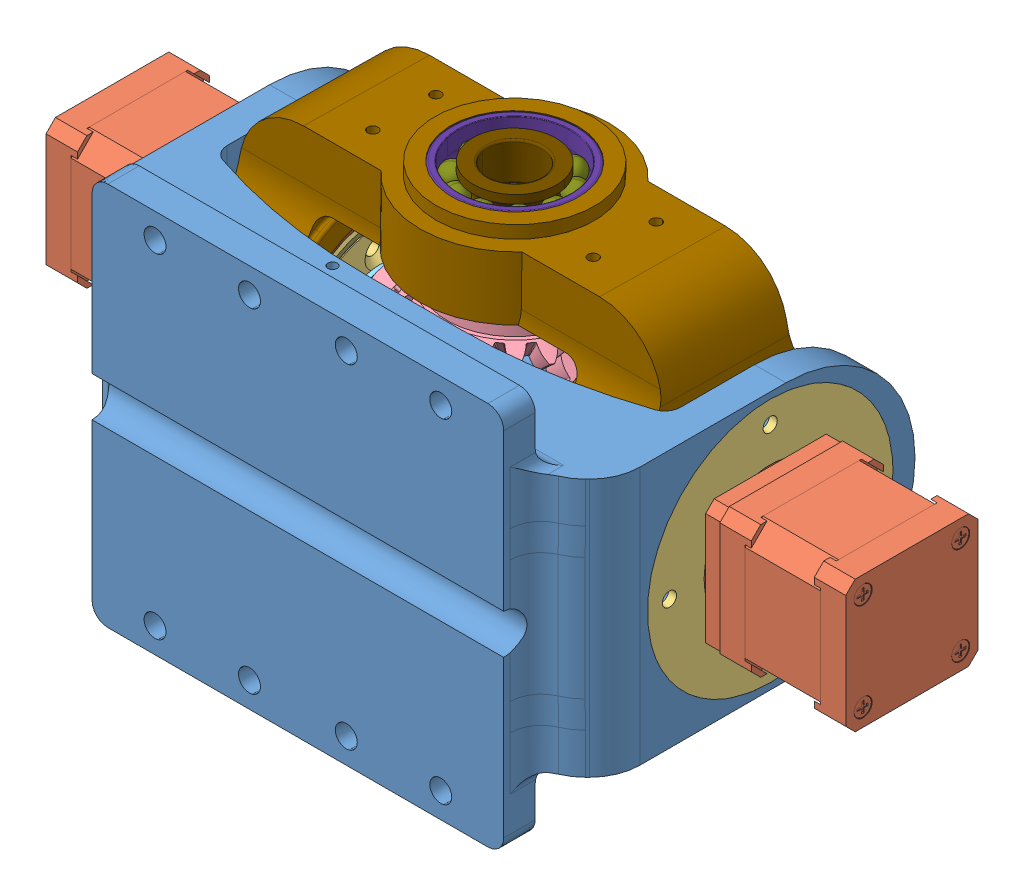
SolidWorks assembly UOM20-4A004, configuration Default. Lengths in mm.
Overall size (254 124.53 114).
231 component instances, 22 part files, 40 mates.
Components (placement in the parent):
- Wrist input frame-1: Wrist input frame [Default] at (121.1695 -112.5132 10.5195) x (0 0 1) z (-1 0 0) size (114 122 164)
- 17HS15-1684D-HG10-AR3-1: 17HS15-1684D-HG10-AR3 [Default] at (87 0 -68) x (0 0 -1) z (-1 0 0) size (42.88 42 103.5)
- Motor sleeve-1: Motor sleeve [Default] at (82 0 -68) x (-1 0 0) z (0 0 1) size (40 78 78)
- straight miter gear_am-1: straight miter gear_am [A 1C 4MYKW25020] at (27.6259 0 -68) x (-1 0 0) z (0 -0.979897 0.199505) size (19.66 53.34 53.34)
- 1.5mm spacer-3: 1.5mm spacer [Default] at (37 0 -68) x (0 0 -1) z (1 0 0) size (28 28 1.5)
- AXK_1528___AS_1528___AS_1528-2: AXK_1528___AS_1528___AS_1528 [Default] at (39.5 0 -68) size (4 28 28)
  - AXK_1528___AS_1528___AS_1528_3-1: AXK_1528___AS_1528___AS_1528_3 [Default] x (1 0 0) z (0 -0.309017 0.951057) size (2 5 2)
  - AXK_1528___AS_1528___AS_1528_3-2: AXK_1528___AS_1528___AS_1528_3 [Default] x (1 0 0) z (0 -0.587785 0.809017) size (2 5 2)
  - AXK_1528___AS_1528___AS_1528_3-3: AXK_1528___AS_1528___AS_1528_3 [Default] x (1 0 0) z (0 -0.809017 0.587785) size (2 5 2)
  - AXK_1528___AS_1528___AS_1528_3-4: AXK_1528___AS_1528___AS_1528_3 [Default] x (1 0 0) z (0 -0.951057 0.309017) size (2 5 2)
  - AXK_1528___AS_1528___AS_1528_3-5: AXK_1528___AS_1528___AS_1528_3 [Default] x (1 0 0) z (0 -1 0) size (2 5 2)
  - AXK_1528___AS_1528___AS_1528_3-6: AXK_1528___AS_1528___AS_1528_3 [Default] x (1 0 0) z (0 -0.951057 -0.309017) size (2 5 2)
  - AXK_1528___AS_1528___AS_1528_3-7: AXK_1528___AS_1528___AS_1528_3 [Default] x (1 0 0) z (0 -0.809017 -0.587785) size (2 5 2)
  - AXK_1528___AS_1528___AS_1528_3-8: AXK_1528___AS_1528___AS_1528_3 [Default] x (1 0 0) z (0 -0.587785 -0.809017) size (2 5 2)
  - AXK_1528___AS_1528___AS_1528_3-9: AXK_1528___AS_1528___AS_1528_3 [Default] x (1 0 0) z (0 -0.309017 -0.951057) size (2 5 2)
  - AXK_1528___AS_1528___AS_1528_3-10: AXK_1528___AS_1528___AS_1528_3 [Default] x (1 0 0) z (0 0 -1) size (2 5 2)
  - AXK_1528___AS_1528___AS_1528_3-11: AXK_1528___AS_1528___AS_1528_3 [Default] x (1 0 0) z (0 0.309017 -0.951057) size (2 5 2)
  - AXK_1528___AS_1528___AS_1528_3-12: AXK_1528___AS_1528___AS_1528_3 [Default] x (1 0 0) z (0 0.587785 -0.809017) size (2 5 2)
  - AXK_1528___AS_1528___AS_1528_3-13: AXK_1528___AS_1528___AS_1528_3 [Default] x (1 0 0) z (0 0.809017 -0.587785) size (2 5 2)
  - AXK_1528___AS_1528___AS_1528_3-14: AXK_1528___AS_1528___AS_1528_3 [Default] x (1 0 0) z (0 0.951057 -0.309017) size (2 5 2)
  - AXK_1528___AS_1528___AS_1528_3-15: AXK_1528___AS_1528___AS_1528_3 [Default] x (1 0 0) z (0 1 0) size (2 5 2)
  - AXK_1528___AS_1528___AS_1528_3-16: AXK_1528___AS_1528___AS_1528_3 [Default] x (1 0 0) z (0 0.951057 0.309017) size (2 5 2)
  - AXK_1528___AS_1528___AS_1528_3-17: AXK_1528___AS_1528___AS_1528_3 [Default] x (1 0 0) z (0 0.809017 0.587785) size (2 5 2)
  - AXK_1528___AS_1528___AS_1528_3-18: AXK_1528___AS_1528___AS_1528_3 [Default] x (1 0 0) z (0 0.587785 0.809017) size (2 5 2)
  - AXK_1528___AS_1528___AS_1528_3-19: AXK_1528___AS_1528___AS_1528_3 [Default] x (1 0 0) z (0 0.309017 0.951057) size (2 5 2)
  - AXK_1528___AS_1528___AS_1528_3-20: AXK_1528___AS_1528___AS_1528_3 [Default] at origin size (2 5 2)
  - AXK_1528___AS_1528___AS_1528_24-1: AXK_1528___AS_1528___AS_1528_24 [Default] at origin size (1 28 28) (hidden)
  - AXK_1528___AS_1528___AS_1528_26-1: AXK_1528___AS_1528___AS_1528_26 [Default] at origin size (1 28 28) (hidden)
  - AXK_1528___AS_1528___AS_1528_28-1: AXK_1528___AS_1528___AS_1528_28 [Default] at origin size (1.6 28 28)
- 1.5mm spacer-4: 1.5mm spacer [Default] at (42 0 -68) x (0 0.929021 0.370027) z (-1 0 0) size (28 28 1.5)
- Input shaft-1: Input shaft [Default] at (42 0 -68) x (-1 0 0) z (0 0.979897 -0.199505) size (42 17 17)
- Wrist output frame-1: Wrist output frame [Default] at (-67 0 -68) x (1 0 0) z (0 0.013642 0.999907) size (134 102 78)
- NKI_50_25-1: NKI_50_25 [Default] at (-67 0 -68) size (25 68.42 68)
  - NKI_50_25_37-1: NKI_50_25_37 [Default] x (1 0 0) z (0 -0.189251 0.981929) size (18.8 3.5 3.5)
  - NKI_50_25_37-2: NKI_50_25_37 [Default] x (1 0 0) z (0 -0.371662 0.928368) size (18.8 3.5 3.5)
  - NKI_50_25_37-3: NKI_50_25_37 [Default] x (1 0 0) z (0 -0.540641 0.841254) size (18.8 3.5 3.5)
  - NKI_50_25_37-4: NKI_50_25_37 [Default] x (1 0 0) z (0 -0.690079 0.723734) size (18.8 3.5 3.5)
  - NKI_50_25_37-5: NKI_50_25_37 [Default] x (1 0 0) z (0 -0.814576 0.580057) size (18.8 3.5 3.5)
  - NKI_50_25_37-6: NKI_50_25_37 [Default] x (1 0 0) z (0 -0.909632 0.415415) size (18.8 3.5 3.5)
  - NKI_50_25_37-7: NKI_50_25_37 [Default] x (1 0 0) z (0 -0.971812 0.235759) size (18.8 3.5 3.5)
  - NKI_50_25_37-8: NKI_50_25_37 [Default] x (1 0 0) z (0 -0.998867 0.047582) size (18.8 3.5 3.5)
  - NKI_50_25_37-9: NKI_50_25_37 [Default] x (1 0 0) z (0 -0.989821 -0.142315) size (18.8 3.5 3.5)
  - NKI_50_25_37-10: NKI_50_25_37 [Default] x (1 0 0) z (0 -0.945001 -0.327068) size (18.8 3.5 3.5)
  - NKI_50_25_37-11: NKI_50_25_37 [Default] x (1 0 0) z (0 -0.866025 -0.5) size (18.8 3.5 3.5)
  - NKI_50_25_37-12: NKI_50_25_37 [Default] x (1 0 0) z (0 -0.75575 -0.654861) size (18.8 3.5 3.5)
  - NKI_50_25_37-13: NKI_50_25_37 [Default] x (1 0 0) z (0 -0.618159 -0.786053) size (18.8 3.5 3.5)
  - NKI_50_25_37-14: NKI_50_25_37 [Default] x (1 0 0) z (0 -0.458227 -0.888835) size (18.8 3.5 3.5)
  - NKI_50_25_37-15: NKI_50_25_37 [Default] x (1 0 0) z (0 -0.281733 -0.959493) size (18.8 3.5 3.5)
  - NKI_50_25_37-16: NKI_50_25_37 [Default] x (1 0 0) z (0 -0.095056 -0.995472) size (18.8 3.5 3.5)
  - NKI_50_25_37-17: NKI_50_25_37 [Default] x (1 0 0) z (0 0.095056 -0.995472) size (18.8 3.5 3.5)
  - NKI_50_25_37-18: NKI_50_25_37 [Default] x (1 0 0) z (0 0.281733 -0.959493) size (18.8 3.5 3.5)
  - NKI_50_25_37-19: NKI_50_25_37 [Default] x (1 0 0) z (0 0.458227 -0.888835) size (18.8 3.5 3.5)
  - NKI_50_25_37-20: NKI_50_25_37 [Default] x (1 0 0) z (0 0.618159 -0.786053) size (18.8 3.5 3.5)
  - NKI_50_25_37-21: NKI_50_25_37 [Default] x (1 0 0) z (0 0.75575 -0.654861) size (18.8 3.5 3.5)
  - NKI_50_25_37-22: NKI_50_25_37 [Default] x (1 0 0) z (0 0.866025 -0.5) size (18.8 3.5 3.5)
  - NKI_50_25_37-23: NKI_50_25_37 [Default] x (1 0 0) z (0 0.945001 -0.327068) size (18.8 3.5 3.5)
  - NKI_50_25_37-24: NKI_50_25_37 [Default] x (1 0 0) z (0 0.989821 -0.142315) size (18.8 3.5 3.5)
  - NKI_50_25_37-25: NKI_50_25_37 [Default] x (1 0 0) z (0 0.998867 0.047582) size (18.8 3.5 3.5)
  - NKI_50_25_37-26: NKI_50_25_37 [Default] x (1 0 0) z (0 0.971812 0.235759) size (18.8 3.5 3.5)
  - NKI_50_25_37-27: NKI_50_25_37 [Default] x (1 0 0) z (0 0.909632 0.415415) size (18.8 3.5 3.5)
  - NKI_50_25_37-28: NKI_50_25_37 [Default] x (1 0 0) z (0 0.814576 0.580057) size (18.8 3.5 3.5)
  - NKI_50_25_37-29: NKI_50_25_37 [Default] x (1 0 0) z (0 0.690079 0.723734) size (18.8 3.5 3.5)
  - NKI_50_25_37-30: NKI_50_25_37 [Default] x (1 0 0) z (0 0.540641 0.841254) size (18.8 3.5 3.5)
  - NKI_50_25_37-31: NKI_50_25_37 [Default] x (1 0 0) z (0 0.371662 0.928368) size (18.8 3.5 3.5)
  - NKI_50_25_37-32: NKI_50_25_37 [Default] x (1 0 0) z (0 0.189251 0.981929) size (18.8 3.5 3.5)
  - NKI_50_25_37-33: NKI_50_25_37 [Default] at origin size (18.8 3.5 3.5)
  - NKI_50_25_71-1: NKI_50_25_71 [Default] at origin size (25 68.42 68)
  - NKI_50_25_73-1: NKI_50_25_73 [Default] at origin size (25 55 55)
- HK_1412-1: HK_1412 [Default] at (-15 0 -68) x (1 0 0) z (0 0.280515 0.95985) size (12 20 20)
  - HK_1412_3-1: HK_1412_3 [Default] x (1 0 0) z (0 -0.382683 0.92388) size (7.3 2 2)
  - HK_1412_3-2: HK_1412_3 [Default] x (1 0 0) z (0 -0.707107 0.707107) size (7.3 2 2)
  - HK_1412_3-3: HK_1412_3 [Default] x (1 0 0) z (0 -0.92388 0.382683) size (7.3 2 2)
  - HK_1412_3-4: HK_1412_3 [Default] x (1 0 0) z (0 -1 0) size (7.3 2 2)
  - HK_1412_3-5: HK_1412_3 [Default] x (1 0 0) z (0 -0.92388 -0.382683) size (7.3 2 2)
  - HK_1412_3-6: HK_1412_3 [Default] x (1 0 0) z (0 -0.707107 -0.707107) size (7.3 2 2)
  - HK_1412_3-7: HK_1412_3 [Default] x (1 0 0) z (0 -0.382683 -0.92388) size (7.3 2 2)
  - HK_1412_3-8: HK_1412_3 [Default] x (1 0 0) z (0 0 -1) size (7.3 2 2)
  - HK_1412_3-9: HK_1412_3 [Default] x (1 0 0) z (0 0.382683 -0.92388) size (7.3 2 2)
  - HK_1412_3-10: HK_1412_3 [Default] x (1 0 0) z (0 0.707107 -0.707107) size (7.3 2 2)
  - HK_1412_3-11: HK_1412_3 [Default] x (1 0 0) z (0 0.92388 -0.382683) size (7.3 2 2)
  - HK_1412_3-12: HK_1412_3 [Default] x (1 0 0) z (0 1 0) size (7.3 2 2)
  - HK_1412_3-13: HK_1412_3 [Default] x (1 0 0) z (0 0.92388 0.382683) size (7.3 2 2)
  - HK_1412_3-14: HK_1412_3 [Default] x (1 0 0) z (0 0.707107 0.707107) size (7.3 2 2)
  - HK_1412_3-15: HK_1412_3 [Default] x (1 0 0) z (0 0.382683 0.92388) size (7.3 2 2)
  - HK_1412_3-16: HK_1412_3 [Default] at origin size (7.3 2 2)
  - HK_1412_20-1: HK_1412_20 [Default] x (1 0 0) z (0 -0.382683 0.92388) size (7.3 2 2)
  - HK_1412_20-2: HK_1412_20 [Default] x (1 0 0) z (0 -0.707107 0.707107) size (7.3 2 2)
  - HK_1412_20-3: HK_1412_20 [Default] x (1 0 0) z (0 -0.92388 0.382683) size (7.3 2 2)
  - HK_1412_20-4: HK_1412_20 [Default] x (1 0 0) z (0 -1 0) size (7.3 2 2)
  - HK_1412_20-5: HK_1412_20 [Default] x (1 0 0) z (0 -0.92388 -0.382683) size (7.3 2 2)
  - HK_1412_20-6: HK_1412_20 [Default] x (1 0 0) z (0 -0.707107 -0.707107) size (7.3 2 2)
  - HK_1412_20-7: HK_1412_20 [Default] x (1 0 0) z (0 -0.382683 -0.92388) size (7.3 2 2)
  - HK_1412_20-8: HK_1412_20 [Default] x (1 0 0) z (0 0 -1) size (7.3 2 2)
  - HK_1412_20-9: HK_1412_20 [Default] x (1 0 0) z (0 0.382683 -0.92388) size (7.3 2 2)
  - HK_1412_20-10: HK_1412_20 [Default] x (1 0 0) z (0 0.707107 -0.707107) size (7.3 2 2)
  - HK_1412_20-11: HK_1412_20 [Default] x (1 0 0) z (0 0.92388 -0.382683) size (7.3 2 2)
  - HK_1412_20-12: HK_1412_20 [Default] x (1 0 0) z (0 1 0) size (7.3 2 2)
  - HK_1412_20-13: HK_1412_20 [Default] x (1 0 0) z (0 0.92388 0.382683) size (7.3 2 2)
  - HK_1412_20-14: HK_1412_20 [Default] x (1 0 0) z (0 0.707107 0.707107) size (7.3 2 2)
  - HK_1412_20-15: HK_1412_20 [Default] x (1 0 0) z (0 0.382683 0.92388) size (7.3 2 2)
  - HK_1412_20-16: HK_1412_20 [Default] at origin size (7.3 2 2)
  - HK_1412_37-1: HK_1412_37 [Default] at origin size (12 20 20)
- Output shaft-1: Output shaft [Default] at (0 18.9482 -68.2585) x (-0.666543 0.01017 0.745397) z (0 0.999907 -0.013642) size (110 110 15) (hidden)
- 7203_BEY-1: 7203_BEY [Default] at (0 38.9964 -68.532) x (0 0.999907 -0.013642) z (0.969629 -0.003337 -0.244559) size (12 40 40)
  - 7203_BEY_3-1: 7203_BEY_3 [Default] x (1 0 0) z (0 -0.587785 0.809017) size (7.14 7.14 7.14)
  - 7203_BEY_3-2: 7203_BEY_3 [Default] x (1 0 0) z (0 -0.951057 0.309017) size (7.14 7.14 7.14)
  - 7203_BEY_3-3: 7203_BEY_3 [Default] x (1 0 0) z (0 -0.951057 -0.309017) size (7.14 7.14 7.14)
  - 7203_BEY_3-4: 7203_BEY_3 [Default] x (1 0 0) z (0 -0.587785 -0.809017) size (7.14 7.14 7.14)
  - 7203_BEY_3-5: 7203_BEY_3 [Default] x (1 0 0) z (0 0 -1) size (7.14 7.14 7.14)
  - 7203_BEY_3-6: 7203_BEY_3 [Default] x (1 0 0) z (0 0.587785 -0.809017) size (7.14 7.14 7.14)
  - 7203_BEY_3-7: 7203_BEY_3 [Default] x (1 0 0) z (0 0.951057 -0.309017) size (7.14 7.14 7.14)
  - 7203_BEY_3-8: 7203_BEY_3 [Default] x (1 0 0) z (0 0.951057 0.309017) size (7.14 7.14 7.14)
  - 7203_BEY_3-9: 7203_BEY_3 [Default] x (1 0 0) z (0 0.587785 0.809017) size (7.14 7.14 7.14)
  - 7203_BEY_3-10: 7203_BEY_3 [Default] at origin size (7.14 7.14 7.14)
  - 7203_BEY_14-1: 7203_BEY_14 [Default] at origin size (12 40 40)
  - 7203_BEY_16-1: 7203_BEY_16 [Default] at origin size (12 26.25 26.25)
- 7203_BEY-2: 7203_BEY [Default] at (0 50.9953 -68.6957) x (0 0.999907 -0.013642) z (0.973748 -0.003105 -0.227608) size (12 40 40)
  - 7203_BEY_3-1: 7203_BEY_3 [Default] x (1 0 0) z (0 -0.587785 0.809017) size (7.14 7.14 7.14)
  - 7203_BEY_3-2: 7203_BEY_3 [Default] x (1 0 0) z (0 -0.951057 0.309017) size (7.14 7.14 7.14)
  - 7203_BEY_3-3: 7203_BEY_3 [Default] x (1 0 0) z (0 -0.951057 -0.309017) size (7.14 7.14 7.14)
  - 7203_BEY_3-4: 7203_BEY_3 [Default] x (1 0 0) z (0 -0.587785 -0.809017) size (7.14 7.14 7.14)
  - 7203_BEY_3-5: 7203_BEY_3 [Default] x (1 0 0) z (0 0 -1) size (7.14 7.14 7.14)
  - 7203_BEY_3-6: 7203_BEY_3 [Default] x (1 0 0) z (0 0.587785 -0.809017) size (7.14 7.14 7.14)
  - 7203_BEY_3-7: 7203_BEY_3 [Default] x (1 0 0) z (0 0.951057 -0.309017) size (7.14 7.14 7.14)
  - 7203_BEY_3-8: 7203_BEY_3 [Default] x (1 0 0) z (0 0.951057 0.309017) size (7.14 7.14 7.14)
  - 7203_BEY_3-9: 7203_BEY_3 [Default] x (1 0 0) z (0 0.587785 0.809017) size (7.14 7.14 7.14)
  - 7203_BEY_3-10: 7203_BEY_3 [Default] at origin size (7.14 7.14 7.14)
  - 7203_BEY_14-1: 7203_BEY_14 [Default] at origin size (12 40 40)
  - 7203_BEY_16-1: 7203_BEY_16 [Default] at origin size (12 26.25 26.25)
- straight miter gear_am-3: straight miter gear_am [A 1C 4MYKW25020] at (0 29.6232 -68.4042) x (0 -0.999907 0.013642) z (0.288342 -0.013063 -0.957438) size (19.66 53.34 53.34)
- Wrist output cap-1: Wrist output cap [Default] at (0 62.9941 -68.8594) x (-1 0 0) z (0 0.999907 -0.013642) size (94 60 6.33) (hidden)
- straight miter gear_am-2: straight miter gear_am [A 1C 4MYKW25020] at (-27.6259 0 -68) x (1 0 0) z (0 0.979897 -0.199505) size (19.66 53.34 53.34)
- 1.5mm spacer-5: 1.5mm spacer [Default] at (-38.5 0 -68) x (0 0 -1) z (1 0 0) size (28 28 1.5)
- AXK_1528___AS_1528___AS_1528-3: AXK_1528___AS_1528___AS_1528 [Default] at (-39.5 0 -68) x (-1 0 0) z (0 0 -1) size (4 28 28)
  - AXK_1528___AS_1528___AS_1528_3-1: AXK_1528___AS_1528___AS_1528_3 [Default] x (1 0 0) z (0 -0.309017 0.951057) size (2 5 2)
  - AXK_1528___AS_1528___AS_1528_3-2: AXK_1528___AS_1528___AS_1528_3 [Default] x (1 0 0) z (0 -0.587785 0.809017) size (2 5 2)
  - AXK_1528___AS_1528___AS_1528_3-3: AXK_1528___AS_1528___AS_1528_3 [Default] x (1 0 0) z (0 -0.809017 0.587785) size (2 5 2)
  - AXK_1528___AS_1528___AS_1528_3-4: AXK_1528___AS_1528___AS_1528_3 [Default] x (1 0 0) z (0 -0.951057 0.309017) size (2 5 2)
  - AXK_1528___AS_1528___AS_1528_3-5: AXK_1528___AS_1528___AS_1528_3 [Default] x (1 0 0) z (0 -1 0) size (2 5 2)
  - AXK_1528___AS_1528___AS_1528_3-6: AXK_1528___AS_1528___AS_1528_3 [Default] x (1 0 0) z (0 -0.951057 -0.309017) size (2 5 2)
  - AXK_1528___AS_1528___AS_1528_3-7: AXK_1528___AS_1528___AS_1528_3 [Default] x (1 0 0) z (0 -0.809017 -0.587785) size (2 5 2)
  - AXK_1528___AS_1528___AS_1528_3-8: AXK_1528___AS_1528___AS_1528_3 [Default] x (1 0 0) z (0 -0.587785 -0.809017) size (2 5 2)
  - AXK_1528___AS_1528___AS_1528_3-9: AXK_1528___AS_1528___AS_1528_3 [Default] x (1 0 0) z (0 -0.309017 -0.951057) size (2 5 2)
  - AXK_1528___AS_1528___AS_1528_3-10: AXK_1528___AS_1528___AS_1528_3 [Default] x (1 0 0) z (0 0 -1) size (2 5 2)
  - AXK_1528___AS_1528___AS_1528_3-11: AXK_1528___AS_1528___AS_1528_3 [Default] x (1 0 0) z (0 0.309017 -0.951057) size (2 5 2)
  - AXK_1528___AS_1528___AS_1528_3-12: AXK_1528___AS_1528___AS_1528_3 [Default] x (1 0 0) z (0 0.587785 -0.809017) size (2 5 2)
  - AXK_1528___AS_1528___AS_1528_3-13: AXK_1528___AS_1528___AS_1528_3 [Default] x (1 0 0) z (0 0.809017 -0.587785) size (2 5 2)
  - AXK_1528___AS_1528___AS_1528_3-14: AXK_1528___AS_1528___AS_1528_3 [Default] x (1 0 0) z (0 0.951057 -0.309017) size (2 5 2)
  - AXK_1528___AS_1528___AS_1528_3-15: AXK_1528___AS_1528___AS_1528_3 [Default] x (1 0 0) z (0 1 0) size (2 5 2)
  - AXK_1528___AS_1528___AS_1528_3-16: AXK_1528___AS_1528___AS_1528_3 [Default] x (1 0 0) z (0 0.951057 0.309017) size (2 5 2)
  - AXK_1528___AS_1528___AS_1528_3-17: AXK_1528___AS_1528___AS_1528_3 [Default] x (1 0 0) z (0 0.809017 0.587785) size (2 5 2)
  - AXK_1528___AS_1528___AS_1528_3-18: AXK_1528___AS_1528___AS_1528_3 [Default] x (1 0 0) z (0 0.587785 0.809017) size (2 5 2)
  - AXK_1528___AS_1528___AS_1528_3-19: AXK_1528___AS_1528___AS_1528_3 [Default] x (1 0 0) z (0 0.309017 0.951057) size (2 5 2)
  - AXK_1528___AS_1528___AS_1528_3-20: AXK_1528___AS_1528___AS_1528_3 [Default] at origin size (2 5 2)
  - AXK_1528___AS_1528___AS_1528_24-1: AXK_1528___AS_1528___AS_1528_24 [Default] at origin size (1 28 28) (hidden)
  - AXK_1528___AS_1528___AS_1528_26-1: AXK_1528___AS_1528___AS_1528_26 [Default] at origin size (1 28 28) (hidden)
  - AXK_1528___AS_1528___AS_1528_28-1: AXK_1528___AS_1528___AS_1528_28 [Default] at origin size (1.6 28 28)
- 1.5mm spacer-6: 1.5mm spacer [Default] at (-40.5 0 -68) x (0 0.929021 0.370027) z (-1 0 0) size (28 28 1.5)
- Input shaft-2: Input shaft [Default] at (-42 0 -68) x (1 0 0) z (0 -0.979897 0.199505) size (42 17 17)
- HK_1412-2: HK_1412 [Default] at (15 0 -68) x (-1 0 0) z (0 -0.280515 -0.95985) size (12 20 20)
  - HK_1412_3-1: HK_1412_3 [Default] x (1 0 0) z (0 -0.382683 0.92388) size (7.3 2 2)
  - HK_1412_3-2: HK_1412_3 [Default] x (1 0 0) z (0 -0.707107 0.707107) size (7.3 2 2)
  - HK_1412_3-3: HK_1412_3 [Default] x (1 0 0) z (0 -0.92388 0.382683) size (7.3 2 2)
  - HK_1412_3-4: HK_1412_3 [Default] x (1 0 0) z (0 -1 0) size (7.3 2 2)
  - HK_1412_3-5: HK_1412_3 [Default] x (1 0 0) z (0 -0.92388 -0.382683) size (7.3 2 2)
  - HK_1412_3-6: HK_1412_3 [Default] x (1 0 0) z (0 -0.707107 -0.707107) size (7.3 2 2)
  - HK_1412_3-7: HK_1412_3 [Default] x (1 0 0) z (0 -0.382683 -0.92388) size (7.3 2 2)
  - HK_1412_3-8: HK_1412_3 [Default] x (1 0 0) z (0 0 -1) size (7.3 2 2)
  - HK_1412_3-9: HK_1412_3 [Default] x (1 0 0) z (0 0.382683 -0.92388) size (7.3 2 2)
  - HK_1412_3-10: HK_1412_3 [Default] x (1 0 0) z (0 0.707107 -0.707107) size (7.3 2 2)
  - HK_1412_3-11: HK_1412_3 [Default] x (1 0 0) z (0 0.92388 -0.382683) size (7.3 2 2)
  - HK_1412_3-12: HK_1412_3 [Default] x (1 0 0) z (0 1 0) size (7.3 2 2)
  - HK_1412_3-13: HK_1412_3 [Default] x (1 0 0) z (0 0.92388 0.382683) size (7.3 2 2)
  - HK_1412_3-14: HK_1412_3 [Default] x (1 0 0) z (0 0.707107 0.707107) size (7.3 2 2)
  - HK_1412_3-15: HK_1412_3 [Default] x (1 0 0) z (0 0.382683 0.92388) size (7.3 2 2)
  - HK_1412_3-16: HK_1412_3 [Default] at origin size (7.3 2 2)
  - HK_1412_20-1: HK_1412_20 [Default] x (1 0 0) z (0 -0.382683 0.92388) size (7.3 2 2)
  - HK_1412_20-2: HK_1412_20 [Default] x (1 0 0) z (0 -0.707107 0.707107) size (7.3 2 2)
  - HK_1412_20-3: HK_1412_20 [Default] x (1 0 0) z (0 -0.92388 0.382683) size (7.3 2 2)
  - HK_1412_20-4: HK_1412_20 [Default] x (1 0 0) z (0 -1 0) size (7.3 2 2)
  - HK_1412_20-5: HK_1412_20 [Default] x (1 0 0) z (0 -0.92388 -0.382683) size (7.3 2 2)
  - HK_1412_20-6: HK_1412_20 [Default] x (1 0 0) z (0 -0.707107 -0.707107) size (7.3 2 2)
  - HK_1412_20-7: HK_1412_20 [Default] x (1 0 0) z (0 -0.382683 -0.92388) size (7.3 2 2)
  - HK_1412_20-8: HK_1412_20 [Default] x (1 0 0) z (0 0 -1) size (7.3 2 2)
  - HK_1412_20-9: HK_1412_20 [Default] x (1 0 0) z (0 0.382683 -0.92388) size (7.3 2 2)
  - HK_1412_20-10: HK_1412_20 [Default] x (1 0 0) z (0 0.707107 -0.707107) size (7.3 2 2)
  - HK_1412_20-11: HK_1412_20 [Default] x (1 0 0) z (0 0.92388 -0.382683) size (7.3 2 2)
  - HK_1412_20-12: HK_1412_20 [Default] x (1 0 0) z (0 1 0) size (7.3 2 2)
  - HK_1412_20-13: HK_1412_20 [Default] x (1 0 0) z (0 0.92388 0.382683) size (7.3 2 2)
  - HK_1412_20-14: HK_1412_20 [Default] x (1 0 0) z (0 0.707107 0.707107) size (7.3 2 2)
  - HK_1412_20-15: HK_1412_20 [Default] x (1 0 0) z (0 0.382683 0.92388) size (7.3 2 2)
  - HK_1412_20-16: HK_1412_20 [Default] at origin size (7.3 2 2)
  - HK_1412_37-1: HK_1412_37 [Default] at origin size (12 20 20)
- 17HS15-1684D-HG10-AR3-2: 17HS15-1684D-HG10-AR3 [Default] at (-87 0 -68) x (0 0 -1) z (1 0 0) size (42.88 42 103.5)
- Motor sleeve-2: Motor sleeve [Default] at (-82 0 -68) size (40 78 78)
- NKI_50_25-2: NKI_50_25 [Default] at (42 0 -68) size (25 68.42 68)
  - NKI_50_25_37-1: NKI_50_25_37 [Default] x (1 0 0) z (0 -0.189251 0.981929) size (18.8 3.5 3.5)
  - NKI_50_25_37-2: NKI_50_25_37 [Default] x (1 0 0) z (0 -0.371662 0.928368) size (18.8 3.5 3.5)
  - NKI_50_25_37-3: NKI_50_25_37 [Default] x (1 0 0) z (0 -0.540641 0.841254) size (18.8 3.5 3.5)
  - NKI_50_25_37-4: NKI_50_25_37 [Default] x (1 0 0) z (0 -0.690079 0.723734) size (18.8 3.5 3.5)
  - NKI_50_25_37-5: NKI_50_25_37 [Default] x (1 0 0) z (0 -0.814576 0.580057) size (18.8 3.5 3.5)
  - NKI_50_25_37-6: NKI_50_25_37 [Default] x (1 0 0) z (0 -0.909632 0.415415) size (18.8 3.5 3.5)
  - NKI_50_25_37-7: NKI_50_25_37 [Default] x (1 0 0) z (0 -0.971812 0.235759) size (18.8 3.5 3.5)
  - NKI_50_25_37-8: NKI_50_25_37 [Default] x (1 0 0) z (0 -0.998867 0.047582) size (18.8 3.5 3.5)
  - NKI_50_25_37-9: NKI_50_25_37 [Default] x (1 0 0) z (0 -0.989821 -0.142315) size (18.8 3.5 3.5)
  - NKI_50_25_37-10: NKI_50_25_37 [Default] x (1 0 0) z (0 -0.945001 -0.327068) size (18.8 3.5 3.5)
  - NKI_50_25_37-11: NKI_50_25_37 [Default] x (1 0 0) z (0 -0.866025 -0.5) size (18.8 3.5 3.5)
  - NKI_50_25_37-12: NKI_50_25_37 [Default] x (1 0 0) z (0 -0.75575 -0.654861) size (18.8 3.5 3.5)
  - NKI_50_25_37-13: NKI_50_25_37 [Default] x (1 0 0) z (0 -0.618159 -0.786053) size (18.8 3.5 3.5)
  - NKI_50_25_37-14: NKI_50_25_37 [Default] x (1 0 0) z (0 -0.458227 -0.888835) size (18.8 3.5 3.5)
  - NKI_50_25_37-15: NKI_50_25_37 [Default] x (1 0 0) z (0 -0.281733 -0.959493) size (18.8 3.5 3.5)
  - NKI_50_25_37-16: NKI_50_25_37 [Default] x (1 0 0) z (0 -0.095056 -0.995472) size (18.8 3.5 3.5)
  - NKI_50_25_37-17: NKI_50_25_37 [Default] x (1 0 0) z (0 0.095056 -0.995472) size (18.8 3.5 3.5)
  - NKI_50_25_37-18: NKI_50_25_37 [Default] x (1 0 0) z (0 0.281733 -0.959493) size (18.8 3.5 3.5)
  - NKI_50_25_37-19: NKI_50_25_37 [Default] x (1 0 0) z (0 0.458227 -0.888835) size (18.8 3.5 3.5)
  - NKI_50_25_37-20: NKI_50_25_37 [Default] x (1 0 0) z (0 0.618159 -0.786053) size (18.8 3.5 3.5)
  - NKI_50_25_37-21: NKI_50_25_37 [Default] x (1 0 0) z (0 0.75575 -0.654861) size (18.8 3.5 3.5)
  - NKI_50_25_37-22: NKI_50_25_37 [Default] x (1 0 0) z (0 0.866025 -0.5) size (18.8 3.5 3.5)
  - NKI_50_25_37-23: NKI_50_25_37 [Default] x (1 0 0) z (0 0.945001 -0.327068) size (18.8 3.5 3.5)
  - NKI_50_25_37-24: NKI_50_25_37 [Default] x (1 0 0) z (0 0.989821 -0.142315) size (18.8 3.5 3.5)
  - NKI_50_25_37-25: NKI_50_25_37 [Default] x (1 0 0) z (0 0.998867 0.047582) size (18.8 3.5 3.5)
  - NKI_50_25_37-26: NKI_50_25_37 [Default] x (1 0 0) z (0 0.971812 0.235759) size (18.8 3.5 3.5)
  - NKI_50_25_37-27: NKI_50_25_37 [Default] x (1 0 0) z (0 0.909632 0.415415) size (18.8 3.5 3.5)
  - NKI_50_25_37-28: NKI_50_25_37 [Default] x (1 0 0) z (0 0.814576 0.580057) size (18.8 3.5 3.5)
  - NKI_50_25_37-29: NKI_50_25_37 [Default] x (1 0 0) z (0 0.690079 0.723734) size (18.8 3.5 3.5)
  - NKI_50_25_37-30: NKI_50_25_37 [Default] x (1 0 0) z (0 0.540641 0.841254) size (18.8 3.5 3.5)
  - NKI_50_25_37-31: NKI_50_25_37 [Default] x (1 0 0) z (0 0.371662 0.928368) size (18.8 3.5 3.5)
  - NKI_50_25_37-32: NKI_50_25_37 [Default] x (1 0 0) z (0 0.189251 0.981929) size (18.8 3.5 3.5)
  - NKI_50_25_37-33: NKI_50_25_37 [Default] at origin size (18.8 3.5 3.5)
  - NKI_50_25_71-1: NKI_50_25_71 [Default] at origin size (25 68.42 68)
  - NKI_50_25_73-1: NKI_50_25_73 [Default] at origin size (25 55 55)
Mates (geometry in assembly coordinates):
- Coincident2: coincident aligned: plane of Wrist input frame-1 through (121.1695 -112.5132 0) normal (0 0 1)
- Symmetric2: symmetric aligned: plane of Wrist input frame-1 through (0 41 -10) normal (0 1 0); plane of Wrist input frame-1 through (0 -41 -10) normal (0 -1 0)
- Symmetric1: symmetric aligned: plane of Wrist input frame-1 through (82 -41 -10) normal (1 0 0); plane of Wrist input frame-1 through (-82 -41 -10) normal (-1 0 0)
- Concentric1: concentric aligned: cylinder of 17HS15-1684D-HG10-AR3-1 through (47 0 -68) axis (1 0 0) radius 21; cylinder of Motor sleeve-1 through (146.1034 0 -68) axis (1 0 0) radius 21
- Concentric2: concentric aligned: cylinder of 17HS15-1684D-HG10-AR3-1 through (47 0 -50.5) axis (-1 0 0) radius 2.25; cylinder of Motor sleeve-1 through (42 0 -50.5) axis (-1 0 0) radius 2.25
- Concentric3: concentric aligned: cylinder of 17HS15-1684D-HG10-AR3-1 through (47 17.5 -68) axis (-1 0 0) radius 2.25; cylinder of Motor sleeve-1 through (42 17.5 -68) axis (-1 0 0) radius 2.25
- Coincident4: coincident anti-aligned: plane of 17HS15-1684D-HG10-AR3-1 through (47 0 -68) normal (-1 0 0); plane of Motor sleeve-1 through (47 -21 -68) normal (1 0 0)
- Concentric4: concentric aligned: cylinder of Wrist input frame-1 through (79.5 0 -68) axis (1 0 0) radius 39; cylinder of Motor sleeve-1 through (146.1034 0 -68) axis (1 0 0) radius 39
- Concentric5: concentric aligned: cylinder of Wrist input frame-1 through (79.5 -32 -68) axis (1 0 0) radius 2.25; cylinder of Motor sleeve-1 through (82 -32 -68) axis (1 0 0) radius 2.25
- Coincident5: coincident anti-aligned: plane of Wrist input frame-1 through (79.5 0 -68) normal (1 0 0); plane of Motor sleeve-1 through (79.5 -26 -68) normal (-1 0 0)
- Concentric9: concentric aligned: cylinder of 17HS15-1684D-HG10-AR3-1 through (39.7 0 -68) axis (1 0 0) radius 4; cylinder of straight miter gear_am-1 through (-7.3741 0 -68) axis (1 0 0) radius 7
- Concentric11: concentric aligned: cylinder of 1.5mm spacer-3 through (38.5 0 -68) axis (-1 0 0) radius 14; cylinder of AXK_1528___AS_1528___AS_1528-2/AXK_1528___AS_1528___AS_1528_28-1 through (40.3 0 -68) axis (-1 0 0) radius 14
- Tangent2: tangent anti-aligned: plane of 1.5mm spacer-3 through (38.5 0 -68) normal (1 0 0); cylinder of AXK_1528___AS_1528___AS_1528-2/AXK_1528___AS_1528___AS_1528_3-10 through (39.5 -8.5 -68) axis (0 1 0) radius 1
- Concentric13: concentric anti-aligned: cylinder of AXK_1528___AS_1528___AS_1528-2/AXK_1528___AS_1528___AS_1528_28-1 through (40.3 0 -68) axis (-1 0 0) radius 14; cylinder of 1.5mm spacer-4 through (40.5 0 -68) axis (1 0 0) radius 14
- Tangent3: tangent anti-aligned: cylinder of AXK_1528___AS_1528___AS_1528-2/AXK_1528___AS_1528___AS_1528_3-11 through (39.5 -8.084 -70.6266) axis (0 0.951057 0.309017) radius 1; plane of 1.5mm spacer-4 through (40.5 0 -68) normal (-1 0 0)
- Coincident10: coincident anti-aligned: plane of Motor sleeve-1 through (42 -8.5 -68) normal (-1 0 0); plane of 1.5mm spacer-4 through (42 0 -68) normal (1 0 0)
- Concentric14: concentric aligned: cylinder of 17HS15-1684D-HG10-AR3-1 through (39.7 0 -68) axis (1 0 0) radius 4; cylinder of Input shaft-1 through (0 0 -68) axis (1 0 0) radius 4
- Concentric15: concentric anti-aligned: cylinder of 17HS15-1684D-HG10-AR3-1 through (39.7 0 -68) axis (1 0 0) radius 4; cylinder of AXK_1528___AS_1528___AS_1528-2/AXK_1528___AS_1528___AS_1528_28-1 through (40.3 0 -68) axis (-1 0 0) radius 14
- Coincident11: coincident anti-aligned: plane of 1.5mm spacer-3 through (37 0 -68) normal (-1 0 0); plane of Input shaft-1 through (37 0 -68) normal (1 0 0)
- Coincident14: coincident anti-aligned: plane of straight miter gear_am-1 through (35 0 -68) normal (1 0 0); plane of Input shaft-1 through (35 0 -68) normal (-1 0 0)
- Concentric16: concentric anti-aligned: cylinder of Wrist output frame-1 through (-42 0 -68) axis (-1 0 0) radius 34; cylinder of NKI_50_25-1/NKI_50_25_71-1 through (-17 0 -68) axis (1 0 0) radius 34
- Coincident15: coincident anti-aligned: plane of Wrist output frame-1 through (-42 0 -68) normal (-1 0 0); plane of NKI_50_25-1/NKI_50_25_71-1 through (-42 31 -68) normal (1 0 0)
- Concentric17: concentric aligned: cylinder of Motor sleeve-1 through (146.1034 0 -68) axis (1 0 0) radius 25; cylinder of Wrist output frame-1 through (42 0 -68) axis (1 0 0) radius 34
- Width1: width aligned: plane of Wrist output frame-1 through (67 0 -68) normal (1 0 0); plane of Wrist input frame-1 through (-67 0 -68) normal (-1 0 0); plane of Wrist output frame-1 through (-72 -41 -114) normal (1 0 0); plane of Wrist input frame-1 through (72 -41 -114) normal (-1 0 0)
- Concentric18: concentric anti-aligned: cylinder of Wrist input frame-1 through (-3 0 -68) axis (-1 0 0) radius 10; cylinder of HK_1412-1/HK_1412_37-1 through (35 0 -68) axis (1 0 0) radius 10
- Coincident16: coincident anti-aligned: plane of Wrist input frame-1 through (-3 0 -68) normal (-1 0 0); plane of HK_1412-1/HK_1412_37-1 through (-3 7.1989 -70.1039) normal (1 0 0)
- Coincident17: coincident anti-aligned: plane of Wrist output frame-1 through (-0.1643 38.9964 -68.532) normal (0 0.999907 -0.013642); plane of 7203_BEY-1/7203_BEY_14-1 through (4.7449 39.253 -49.723) normal (0 -0.999907 0.013642)
- Concentric19: concentric anti-aligned: cylinder of Wrist output frame-1 through (0 58.9955 -68.8049) axis (0 -0.999907 0.013642) radius 20; cylinder of 7203_BEY-1/7203_BEY_14-1 through (0 50.9953 -68.6957) axis (0 0.999907 -0.013642) radius 20
- Concentric20: concentric anti-aligned: cylinder of Wrist output frame-1 through (0 58.9955 -68.8049) axis (0 -0.999907 0.013642) radius 20; cylinder of 7203_BEY-2/7203_BEY_14-1 through (0 62.9941 -68.8594) axis (0 0.999907 -0.013642) radius 20
- Coincident18: coincident anti-aligned: plane of 7203_BEY-1/7203_BEY_14-1 through (4.3902 51.2327 -51.2925) normal (0 0.999907 -0.013642); plane of 7203_BEY-2/7203_BEY_14-1 through (4.416 51.253 -49.8068) normal (0 -0.999907 0.013642)
- Concentric21: concentric: cylinder of Output shaft-1 through (0 0.7067 -130.996) axis (0 -0.011218 0.999937) radius 8.5; cylinder of A 1C 4MYKW25020_15mm bore_modified-1 through (0 -3.1024 -102.2613) axis (0 0.090183 0.995925) radius 7.5
- Concentric22: concentric: cylinder of Output shaft-1 through (0 0.7067 -130.996) axis (0 -0.011218 0.999937) radius 8.5; cylinder of 7203_BEY-2/7203_BEY_16-1 through (0 0.7067 -130.996) axis (0 0.011218 -0.999937) radius 8.5
- Concentric23: concentric anti-aligned: cylinder of Wrist output frame-1 through (0 62.9941 -68.8594) axis (0 -0.999907 0.013642) radius 25; cylinder of Wrist output cap-1 through (0 58.9945 -68.8049) axis (0 0.999907 -0.013642) radius 25
- Parallel2: parallel aligned: plane of Wrist input frame-1 through (-79.5 0 -68) normal (-1 0 0); plane of Wrist output cap-1 through (0 62.9941 -68.8594) normal (-1 0 0)
- Coincident22: coincident anti-aligned: plane of Wrist output frame-1 through (0 58.9945 -68.8049) normal (0 0.999907 -0.013642); plane of Wrist output cap-1 through (0 58.9945 -68.8049) normal (0 -0.999907 0.013642)
- Coincident23: coincident anti-aligned: plane of Output shaft-1 through (0 62.9941 -68.8594) normal (0 -0.999907 0.013642); plane of 7203_BEY-2/7203_BEY_16-1 through (2.0714 63.115 -59.9992) normal (0 0.999907 -0.013642)
- Concentric24: concentric: cylinder of Output shaft-1 through (0 0.4375 -106.9975) axis (0 -0.011218 0.999937) radius 7.5; cylinder of straight miter gear_am-3 through (0 -0.0603 -62.6262) axis (0 0.011218 -0.999937) radius 7
- Coincident24: coincident anti-aligned: plane of Wrist output frame-1 through (-0.1643 36.9966 -68.5048) normal (0 -0.999907 0.013642); plane of straight miter gear_am-3 through (0 36.9966 -68.5048) normal (0 0.999907 -0.013642)
- Concentric25: concentric anti-aligned: cylinder of 7203_BEY-1/7203_BEY_16-1 through (0 50.9953 -68.6957) axis (0 0.999907 -0.013642) radius 8.5; cylinder of straight miter gear_am-3 through (0 36.9966 -68.5048) axis (0 -0.999907 0.013642) radius 21
- Concentric26: concentric aligned: cylinder of Output shaft-1 through (0 77.9927 -69.0641) axis (0 -0.999907 0.013642) radius 55; cylinder of straight miter gear_am-3 through (0 36.9966 -68.5048) axis (0 -0.999907 0.013642) radius 21
